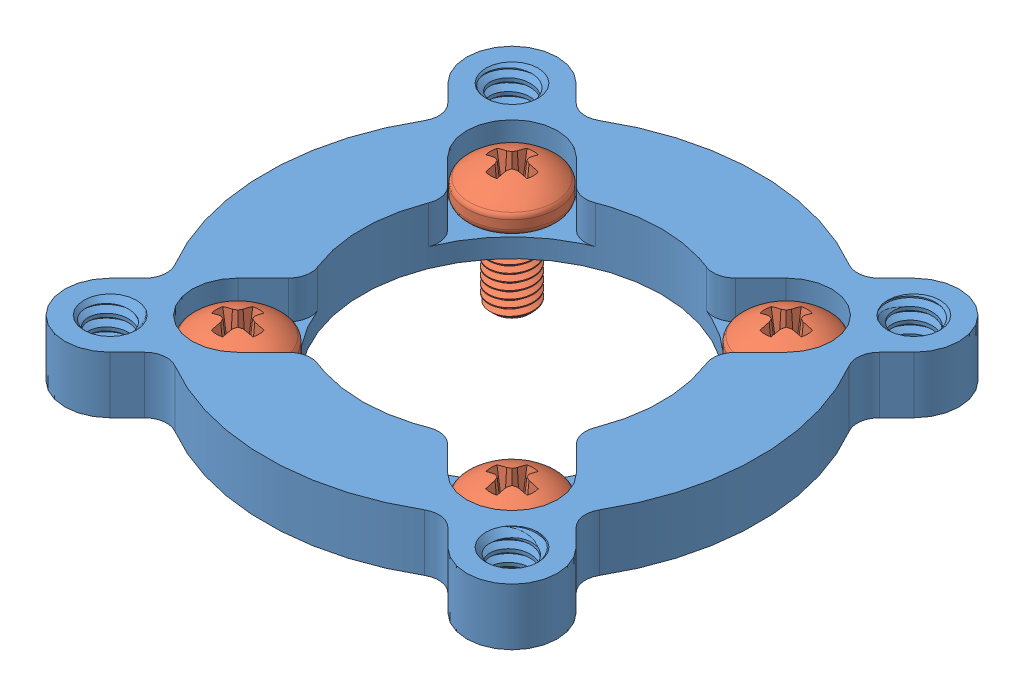
SolidWorks assembly 555174_assembly, configuration Default. Lengths in mm.
Overall size (33.02 8.73 33.02).
5 component instances, 2 part files, 2 mates.
Components (placement in the parent):
- 555174-1: 555174 [Default] at (-9.4107 17.3727 -8.128) size (33.02 4.05 33.02)
- 555174_6-32_3mmx6mm_screw-1: 555174_6-32_3mmx6mm_screw [Default] at (-18.6029 12.6427 -17.3202) x (1 0 0) z (0 1 0) size (6 6 8.48)
- 555174_6-32_3mmx6mm_screw-2: 555174_6-32_3mmx6mm_screw [Default] at (-18.6029 12.6427 1.0642) x (0 0 -1) z (0 1 0) size (6 6 8.48)
- 555174_6-32_3mmx6mm_screw-3: 555174_6-32_3mmx6mm_screw [Default] at (-0.2185 12.6427 1.0642) x (-1 0 0) z (0 1 0) size (6 6 8.48)
- 555174_6-32_3mmx6mm_screw-4: 555174_6-32_3mmx6mm_screw [Default] at (-0.2185 12.6427 -17.3202) x (0 0 1) z (0 1 0) size (6 6 8.48)
Mates (geometry in assembly coordinates):
- Coincident1: coincident anti-aligned: plane of 555174-1 through (-18.6029 18.6427 -17.3202) normal (0 1 0); plane of 555174_6-32_3mmx6mm_screw-1 through (-18.6029 18.6427 -17.3202) normal (0 -1 0)
- Concentric1: concentric anti-aligned: circle of 555174-1; circle of 555174_6-32_3mmx6mm_screw-1
